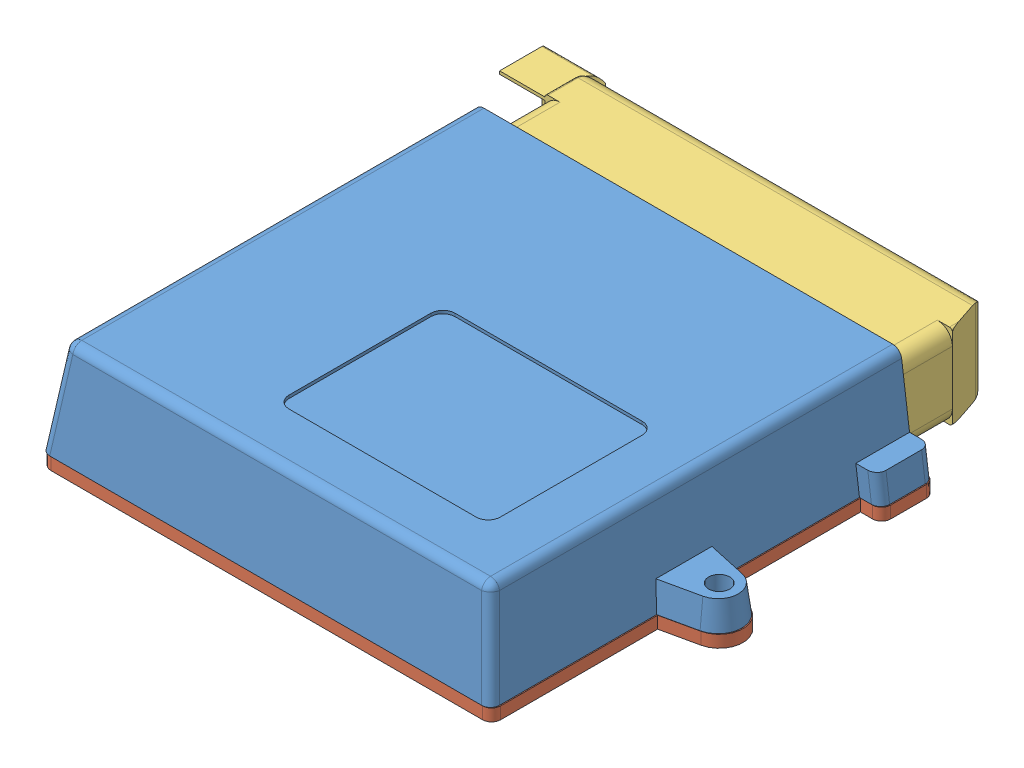
SolidWorks assembly TMBryhn ECU 2.0, configuration Default. Lengths in mm.
Overall size (185.35 35.7 175).
3 component instances, 3 part files, 7 mates.
Components (placement in the parent):
- TMBryhn ECU 2.0_Toppdeksel-1: TMBryhn ECU 2.0_Toppdeksel [Default] at (-61.3931 -9.2927 106.4414) size (185 32.2 157)
- TMBryhn ECU 2.0_Bunnplate-2: TMBryhn ECU 2.0_Bunnplate [Default] at (-61.0431 -13.2927 106.4414) size (185 4 140)
- TMBryhn_ECU 2.0_Connector-1: TMBryhn_ECU 2.0_Connector [Default] at (-61.3931 -9.2927 -33.5586) x (-1 0 0) z (0 0 -1) size (150 28 35)
Mates (geometry in assembly coordinates):
- Coincident3: coincident anti-aligned: plane of TMBryhn ECU 2.0_Toppdeksel-1 through (-61.3931 -9.2927 106.4414) normal (0 -1 0); plane of TMBryhn ECU 2.0_Bunnplate-2 through (23.6069 -9.2927 41.1914) normal (0 1 0)
- Concentric1: concentric aligned: cylinder of TMBryhn ECU 2.0_Toppdeksel-1 through (23.6069 200.7073 41.1914) axis (0 -1 0) radius 3.5; cylinder of TMBryhn ECU 2.0_Bunnplate-2 through (23.6069 -9.2927 41.1914) axis (0 -1 0) radius 3.25
- Coincident4: coincident aligned: plane of TMBryhn ECU 2.0_Toppdeksel-1 through (-61.3931 22.4073 -33.5586) normal (0 0 -1); plane of TMBryhn ECU 2.0_Bunnplate-2 through (-142.5431 -9.2927 -33.5586) normal (0 0 -1)
- InPlace1: in place: plane of TMBryhn ECU 2.0_Toppdeksel-1 through (-61.3931 22.4073 -33.5586) normal (0 0 -1); plane of ? through (0 0 -33.5586) normal (0 0 -1); moOrthogonalPlaneRef_w of TMBryhn ECU 2.0_Toppdeksel-1 through (-61.3931 22.4073 -33.5586) normal (0 0 -1); plane of ? through (0 0 -33.5586) normal (0 1 0); plane of TMBryhn ECU 2.0_Toppdeksel-1 through (-61.3931 22.4073 -33.5586) normal (0 0 -1); plane of ? through (0 0 -33.5586) normal (-1 0 0); plane of TMBryhn ECU 2.0_Toppdeksel-1 through (-61.3931 22.4073 -33.5586) normal (0 0 -1); unknown of TMBryhn_ECU 2.0_Connector-1
- Coincident5: coincident aligned: plane of ?; plane of ?
- Coincident6: coincident aligned: moOrthogonalPlaneRef_w of TMBryhn ECU 2.0_Toppdeksel-1 through (-61.3931 -9.2927 -33.5586) normal (0 1 0); plane of Part1^TMBryhn ECU 2.0-1 through (-61.3931 -9.2927 -33.5586) normal (0 1 0)
- Coincident7: coincident anti-aligned: moOrthogonalPlaneRef_w of TMBryhn ECU 2.0_Toppdeksel-1 through (-61.3931 -9.2927 -33.5586) normal (1 0 0); plane of Part1^TMBryhn ECU 2.0-1 through (-61.3931 -9.2927 -33.5586) normal (-1 0 0)
